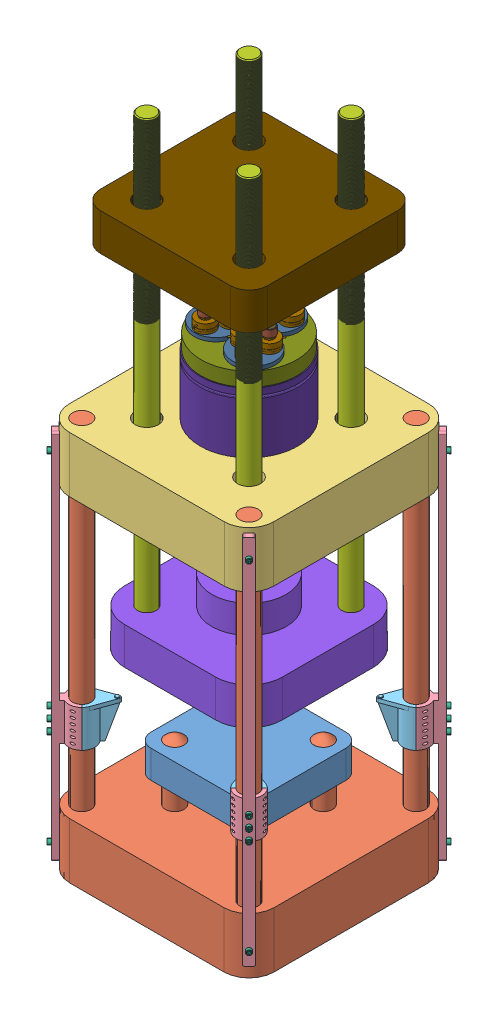
SolidWorks assembly calibration, configuration Default. Lengths in mm.
Overall size (2375.32 7055.28 2375.32).
136 component instances, 18 part files, 43 mates.
Components (placement in the parent):
- montaj alt tabla-1: montaj alt tabla [Default] at (833.2018 170.1758 2167.2273) size (2200.07 4200.02 2200.07)
  - 2 no-3: 2 no [Default] at (132.7753 591.3083 1009.2189) size (1200 300 1200)
  - 1no-3: 1no [Default] at (132.7613 -308.6894 1003.0525) x (1 -0.000003 -0.000025) z (0.000025 -0.000004 1) size (2200 4200 2200)
- orta tabla-1: orta tabla [Default] at (965.9753 3461.4864 3170.2945) x (1 -0.000003 -0.000025) z (0.000025 -0.000004 1) size (2200 900 2200)
- sap montaj-5: sap montaj [Default] at (1404.482 -143.561 155.1917) x (0.707124 -0.000005 0.707089) z (-0.707089 -0.000001 0.707124) size (568.89 4000 280)
  - sap-1: sap [Default] at (549.0564 1205.0583 2442.1143) size (230.77 4000 280)
  - no5-1: no5 [Default] at (549.0564 1605.0583 2442.1143) size (302.12 417 280)
  - socket head cap screw_am-6: socket head cap screw_am [B18.3.1M - 16 x 2.0 x 80 Hex SHCS -- 44NHX] at (503.0564 1555.0583 2562.1143) size (96 24 24)
  - socket head cap screw_am-7: socket head cap screw_am [B18.3.1M - 16 x 2.0 x 80 Hex SHCS -- 44NHX] at (503.0564 1495.0583 2562.1143) size (96 24 24)
  - socket head cap screw_am-8: socket head cap screw_am [B18.3.1M - 16 x 2.0 x 80 Hex SHCS -- 44NHX] at (503.0564 1375.0583 2562.1143) x (1 0 0) z (0 0.323103 0.946364) size (96 24 24)
  - socket head cap screw_am-9: socket head cap screw_am [B18.3.1M - 16 x 2.0 x 80 Hex SHCS -- 44NHX] at (503.0564 1255.0583 2562.1143) size (96 24 24)
  - socket head cap screw_am-10: socket head cap screw_am [B18.3.1M - 16 x 2.0 x 80 Hex SHCS -- 44NHX] at (503.0564 1315.0583 2322.1143) size (96 24 24)
  - socket head cap screw_am-11: socket head cap screw_am [B18.3.1M - 16 x 2.0 x 80 Hex SHCS -- 44NHX] at (503.0564 1435.0583 2562.1143) x (1 0 0) z (0 0 -1) size (96 24 24)
  - socket head cap screw_am-12: socket head cap screw_am [B18.3.1M - 16 x 2.0 x 80 Hex SHCS -- 44NHX] at (503.0564 1255.0583 2322.1143) size (96 24 24)
  - socket head cap screw_am-13: socket head cap screw_am [B18.3.1M - 16 x 2.0 x 80 Hex SHCS -- 44NHX] at (503.0564 1375.0583 2322.1143) size (96 24 24)
  - socket head cap screw_am-14: socket head cap screw_am [B18.3.1M - 16 x 2.0 x 80 Hex SHCS -- 44NHX] at (503.0564 1315.0583 2562.1143) x (1 0 0) z (0 -0.989637 0.143592) size (96 24 24)
  - socket head cap screw_am-15: socket head cap screw_am [B18.3.1M - 16 x 2.0 x 80 Hex SHCS -- 44NHX] at (503.0564 1555.0583 2322.1143) size (96 24 24)
  - socket head cap screw_am-16: socket head cap screw_am [B18.3.1M - 16 x 2.0 x 80 Hex SHCS -- 44NHX] at (503.0564 1495.0583 2322.1143) size (96 24 24)
  - socket head cap screw_am-17: socket head cap screw_am [B18.3.1M - 16 x 2.0 x 80 Hex SHCS -- 44NHX] at (503.0564 1435.0583 2322.1143) size (96 24 24)
  - socket head cap screw_am-19: socket head cap screw_am [B18.3.1M - 36 x 4.0 x 80 Hex SHCS -- 80NHX] at (282.2894 1285.0583 2442.1143) size (116 54 54)
  - socket head cap screw_am-18: socket head cap screw_am [B18.3.1M - 36 x 4.0 x 80 Hex SHCS -- 80NHX] at (282.2894 1525.0583 2442.1143) x (1 0 0) z (0 0.987098 -0.160117) size (116 54 54)
  - socket head cap screw_am-20: socket head cap screw_am [B18.3.1M - 36 x 4.0 x 80 Hex SHCS -- 80NHX] at (282.2894 1405.0583 2442.1143) x (1 0 0) z (0 0.982449 -0.18653) size (116 54 54)
- sap montaj-6: sap montaj [Default] at (527.4443 -93.5827 6185.3679) x (-0.707124 0.000005 -0.707089) z (0.707089 0.000001 -0.707124) size (568.89 4000 280)
  - sap-1: sap [Default] at (549.0564 1205.0583 2442.1143) size (230.77 4000 280)
  - no5-1: no5 [Default] at (549.0564 1605.0583 2442.1143) size (302.12 417 280)
  - socket head cap screw_am-6: socket head cap screw_am [B18.3.1M - 16 x 2.0 x 80 Hex SHCS -- 44NHX] at (503.0564 1555.0583 2562.1143) size (96 24 24)
  - socket head cap screw_am-7: socket head cap screw_am [B18.3.1M - 16 x 2.0 x 80 Hex SHCS -- 44NHX] at (503.0564 1495.0583 2562.1143) size (96 24 24)
  - socket head cap screw_am-8: socket head cap screw_am [B18.3.1M - 16 x 2.0 x 80 Hex SHCS -- 44NHX] at (503.0564 1375.0583 2562.1143) x (1 0 0) z (0 0.323103 0.946364) size (96 24 24)
  - socket head cap screw_am-9: socket head cap screw_am [B18.3.1M - 16 x 2.0 x 80 Hex SHCS -- 44NHX] at (503.0564 1255.0583 2562.1143) size (96 24 24)
  - socket head cap screw_am-10: socket head cap screw_am [B18.3.1M - 16 x 2.0 x 80 Hex SHCS -- 44NHX] at (503.0564 1315.0583 2322.1143) size (96 24 24)
  - socket head cap screw_am-11: socket head cap screw_am [B18.3.1M - 16 x 2.0 x 80 Hex SHCS -- 44NHX] at (503.0564 1435.0583 2562.1143) x (1 0 0) z (0 0 -1) size (96 24 24)
  - socket head cap screw_am-12: socket head cap screw_am [B18.3.1M - 16 x 2.0 x 80 Hex SHCS -- 44NHX] at (503.0564 1255.0583 2322.1143) size (96 24 24)
  - socket head cap screw_am-13: socket head cap screw_am [B18.3.1M - 16 x 2.0 x 80 Hex SHCS -- 44NHX] at (503.0564 1375.0583 2322.1143) size (96 24 24)
  - socket head cap screw_am-14: socket head cap screw_am [B18.3.1M - 16 x 2.0 x 80 Hex SHCS -- 44NHX] at (503.0564 1315.0583 2562.1143) x (1 0 0) z (0 -0.989637 0.143592) size (96 24 24)
  - socket head cap screw_am-15: socket head cap screw_am [B18.3.1M - 16 x 2.0 x 80 Hex SHCS -- 44NHX] at (503.0564 1555.0583 2322.1143) size (96 24 24)
  - socket head cap screw_am-16: socket head cap screw_am [B18.3.1M - 16 x 2.0 x 80 Hex SHCS -- 44NHX] at (503.0564 1495.0583 2322.1143) size (96 24 24)
  - socket head cap screw_am-17: socket head cap screw_am [B18.3.1M - 16 x 2.0 x 80 Hex SHCS -- 44NHX] at (503.0564 1435.0583 2322.1143) size (96 24 24)
  - socket head cap screw_am-19: socket head cap screw_am [B18.3.1M - 36 x 4.0 x 80 Hex SHCS -- 80NHX] at (282.2894 1285.0583 2442.1143) size (116 54 54)
  - socket head cap screw_am-18: socket head cap screw_am [B18.3.1M - 36 x 4.0 x 80 Hex SHCS -- 80NHX] at (282.2894 1525.0583 2442.1143) x (1 0 0) z (0 0.987098 -0.160117) size (116 54 54)
  - socket head cap screw_am-20: socket head cap screw_am [B18.3.1M - 36 x 4.0 x 80 Hex SHCS -- 80NHX] at (282.2894 1405.0583 2442.1143) x (1 0 0) z (0 0.982449 -0.18653) size (116 54 54)
- sap montaj-7: sap montaj [Default] at (-2049.1249 -143.5598 2731.7608) x (0.707089 0.000001 -0.707124) z (0.707124 -0.000005 0.707089) size (568.89 4000 280)
  - sap-1: sap [Default] at (549.0564 1205.0583 2442.1143) size (230.77 4000 280)
  - no5-1: no5 [Default] at (549.0564 1605.0583 2442.1143) size (302.12 417 280)
  - socket head cap screw_am-6: socket head cap screw_am [B18.3.1M - 16 x 2.0 x 80 Hex SHCS -- 44NHX] at (503.0564 1555.0583 2562.1143) size (96 24 24)
  - socket head cap screw_am-7: socket head cap screw_am [B18.3.1M - 16 x 2.0 x 80 Hex SHCS -- 44NHX] at (503.0564 1495.0583 2562.1143) size (96 24 24)
  - socket head cap screw_am-8: socket head cap screw_am [B18.3.1M - 16 x 2.0 x 80 Hex SHCS -- 44NHX] at (503.0564 1375.0583 2562.1143) x (1 0 0) z (0 0.323103 0.946364) size (96 24 24)
  - socket head cap screw_am-9: socket head cap screw_am [B18.3.1M - 16 x 2.0 x 80 Hex SHCS -- 44NHX] at (503.0564 1255.0583 2562.1143) size (96 24 24)
  - socket head cap screw_am-10: socket head cap screw_am [B18.3.1M - 16 x 2.0 x 80 Hex SHCS -- 44NHX] at (503.0564 1315.0583 2322.1143) size (96 24 24)
  - socket head cap screw_am-11: socket head cap screw_am [B18.3.1M - 16 x 2.0 x 80 Hex SHCS -- 44NHX] at (503.0564 1435.0583 2562.1143) x (1 0 0) z (0 0 -1) size (96 24 24)
  - socket head cap screw_am-12: socket head cap screw_am [B18.3.1M - 16 x 2.0 x 80 Hex SHCS -- 44NHX] at (503.0564 1255.0583 2322.1143) size (96 24 24)
  - socket head cap screw_am-13: socket head cap screw_am [B18.3.1M - 16 x 2.0 x 80 Hex SHCS -- 44NHX] at (503.0564 1375.0583 2322.1143) size (96 24 24)
  - socket head cap screw_am-14: socket head cap screw_am [B18.3.1M - 16 x 2.0 x 80 Hex SHCS -- 44NHX] at (503.0564 1315.0583 2562.1143) x (1 0 0) z (0 -0.989637 0.143592) size (96 24 24)
  - socket head cap screw_am-15: socket head cap screw_am [B18.3.1M - 16 x 2.0 x 80 Hex SHCS -- 44NHX] at (503.0564 1555.0583 2322.1143) size (96 24 24)
  - socket head cap screw_am-16: socket head cap screw_am [B18.3.1M - 16 x 2.0 x 80 Hex SHCS -- 44NHX] at (503.0564 1495.0583 2322.1143) size (96 24 24)
  - socket head cap screw_am-17: socket head cap screw_am [B18.3.1M - 16 x 2.0 x 80 Hex SHCS -- 44NHX] at (503.0564 1435.0583 2322.1143) size (96 24 24)
  - socket head cap screw_am-19: socket head cap screw_am [B18.3.1M - 36 x 4.0 x 80 Hex SHCS -- 80NHX] at (282.2894 1285.0583 2442.1143) size (116 54 54)
  - socket head cap screw_am-18: socket head cap screw_am [B18.3.1M - 36 x 4.0 x 80 Hex SHCS -- 80NHX] at (282.2894 1525.0583 2442.1143) x (1 0 0) z (0 0.987098 -0.160117) size (116 54 54)
  - socket head cap screw_am-20: socket head cap screw_am [B18.3.1M - 36 x 4.0 x 80 Hex SHCS -- 80NHX] at (282.2894 1405.0583 2442.1143) x (1 0 0) z (0 0.982449 -0.18653) size (116 54 54)
- sap montaj-8: sap montaj [Default] at (3981.0511 -143.5839 3608.7986) x (-0.707089 -0.000001 0.707124) z (-0.707124 0.000005 -0.707089) size (568.89 4000 280)
  - sap-1: sap [Default] at (549.0564 1205.0583 2442.1143) size (230.77 4000 280)
  - no5-1: no5 [Default] at (549.0564 1605.0583 2442.1143) size (302.12 417 280)
  - socket head cap screw_am-6: socket head cap screw_am [B18.3.1M - 16 x 2.0 x 80 Hex SHCS -- 44NHX] at (503.0564 1555.0583 2562.1143) size (96 24 24)
  - socket head cap screw_am-7: socket head cap screw_am [B18.3.1M - 16 x 2.0 x 80 Hex SHCS -- 44NHX] at (503.0564 1495.0583 2562.1143) size (96 24 24)
  - socket head cap screw_am-8: socket head cap screw_am [B18.3.1M - 16 x 2.0 x 80 Hex SHCS -- 44NHX] at (503.0564 1375.0583 2562.1143) x (1 0 0) z (0 0.323103 0.946364) size (96 24 24)
  - socket head cap screw_am-9: socket head cap screw_am [B18.3.1M - 16 x 2.0 x 80 Hex SHCS -- 44NHX] at (503.0564 1255.0583 2562.1143) size (96 24 24)
  - socket head cap screw_am-10: socket head cap screw_am [B18.3.1M - 16 x 2.0 x 80 Hex SHCS -- 44NHX] at (503.0564 1315.0583 2322.1143) size (96 24 24)
  - socket head cap screw_am-11: socket head cap screw_am [B18.3.1M - 16 x 2.0 x 80 Hex SHCS -- 44NHX] at (503.0564 1435.0583 2562.1143) x (1 0 0) z (0 0 -1) size (96 24 24)
  - socket head cap screw_am-12: socket head cap screw_am [B18.3.1M - 16 x 2.0 x 80 Hex SHCS -- 44NHX] at (503.0564 1255.0583 2322.1143) size (96 24 24)
  - socket head cap screw_am-13: socket head cap screw_am [B18.3.1M - 16 x 2.0 x 80 Hex SHCS -- 44NHX] at (503.0564 1375.0583 2322.1143) size (96 24 24)
  - socket head cap screw_am-14: socket head cap screw_am [B18.3.1M - 16 x 2.0 x 80 Hex SHCS -- 44NHX] at (503.0564 1315.0583 2562.1143) x (1 0 0) z (0 -0.989637 0.143592) size (96 24 24)
  - socket head cap screw_am-15: socket head cap screw_am [B18.3.1M - 16 x 2.0 x 80 Hex SHCS -- 44NHX] at (503.0564 1555.0583 2322.1143) size (96 24 24)
  - socket head cap screw_am-16: socket head cap screw_am [B18.3.1M - 16 x 2.0 x 80 Hex SHCS -- 44NHX] at (503.0564 1495.0583 2322.1143) size (96 24 24)
  - socket head cap screw_am-17: socket head cap screw_am [B18.3.1M - 16 x 2.0 x 80 Hex SHCS -- 44NHX] at (503.0564 1435.0583 2322.1143) size (96 24 24)
  - socket head cap screw_am-19: socket head cap screw_am [B18.3.1M - 36 x 4.0 x 80 Hex SHCS -- 80NHX] at (282.2894 1285.0583 2442.1143) size (116 54 54)
  - socket head cap screw_am-18: socket head cap screw_am [B18.3.1M - 36 x 4.0 x 80 Hex SHCS -- 80NHX] at (282.2894 1525.0583 2442.1143) x (1 0 0) z (0 0.987098 -0.160117) size (116 54 54)
  - socket head cap screw_am-20: socket head cap screw_am [B18.3.1M - 36 x 4.0 x 80 Hex SHCS -- 80NHX] at (282.2894 1405.0583 2442.1143) x (1 0 0) z (0 0.982449 -0.18653) size (116 54 54)
- socket head cap screw_am-1: socket head cap screw_am [B18.3.1M - 36 x 4.0 x 90 Hex SHCS -- 90NHX] at (2054.6363 3811.4783 4258.9015) x (-0.707124 0.000005 -0.707089) z (-0.5112 -0.690889 0.511221) size (126 54 54)
- socket head cap screw_am-2: socket head cap screw_am [B18.3.1M - 36 x 4.0 x 90 Hex SHCS -- 90NHX] at (2054.5819 3761.4872 2081.6359) x (-0.707089 -0.000001 0.707124) z (-0.707124 0.000008 -0.707089) size (126 54 54)
- socket head cap screw_am-3: socket head cap screw_am [B18.3.1M - 36 x 4.0 x 90 Hex SHCS -- 90NHX] at (-122.6293 3761.4856 4258.9556) x (0.707089 0.000001 -0.707124) z (0.500005 -0.707118 0.499979) size (126 54 54)
- socket head cap screw_am-4: socket head cap screw_am [B18.3.1M - 36 x 4.0 x 90 Hex SHCS -- 90NHX] at (-122.6836 3761.4946 2081.6902) x (0.707124 -0.000005 0.707089) z (-0.707089 0.000002 0.707124) size (126 54 54)
- socket head cap screw_am-6: socket head cap screw_am [B18.3.1M - 36 x 4.0 x 120 Hex SHCS -- 84NHX] at (-122.6417 111.4856 4258.9407) x (0.707089 0.000001 -0.707124) z (0.707124 -0.000001 0.707089) size (156 54 54)
- socket head cap screw_am-8: socket head cap screw_am [B18.3.1M - 36 x 4.0 x 120 Hex SHCS -- 84NHX] at (-122.696 111.4946 2081.6752) x (0.707124 -0.000005 0.707089) z (0.124169 -0.98446 -0.124182) size (156 54 54)
- socket head cap screw_am-11: socket head cap screw_am [B18.3.1M - 36 x 4.0 x 120 Hex SHCS -- 84NHX] at (2054.5695 111.4872 2081.6209) x (-0.707089 -0.000001 0.707124) z (-0.707124 0.000001 -0.707089) size (156 54 54)
- socket head cap screw_am-14: socket head cap screw_am [B18.3.1M - 36 x 4.0 x 120 Hex SHCS -- 84NHX] at (2054.624 161.4783 4258.8866) x (-0.707124 0.000005 -0.707089) z (0.707089 -0.000004 -0.707124) size (156 54 54)
- dişli boru-1: dişli boru [Default] at (1515.957 2116.7548 2620.2753) x (-0.603975 -0.000001 0.797003) z (-0.797003 0.000005 -0.603975) size (200 4800 200)
- dişli boru-2: dişli boru [Default] at (1515.9844 2116.7503 3720.2753) x (-0.622585 -0.000001 0.782552) z (-0.782552 0.000005 -0.622585) size (200 4800 200)
- dişli boru-3: dişli boru [Default] at (415.957 2116.7586 2620.3027) x (-0.568311 -0.000001 0.822814) z (-0.822814 0.000005 -0.568311) size (200 4800 200)
- dişli boru-4: dişli boru [Default] at (415.9844 2116.7541 3720.3027) x (0.992602 -0.000004 0.12141) z (-0.12141 -0.000004 0.992602) size (200 4800 200)
- minik tabla-1: minik tabla [Default] at (965.97 1916.7544 3170.2882) x (1 -0.000003 -0.000025) z (0.000025 -0.000004 1) size (1700 735 1700)
- loadcell montaj-1: loadcell montaj [Default] at (1570.4653 4300.1001 2998.6885) x (-0.993338 0.000003 0.11524) z (-0.11524 0.000004 -0.993338) size (1050 1634.29 1115.82)
  - loadcelly-1: loadcelly [Default] at (983.2366 597.3849 -108.9473) x (0.988948 0 0.148261) z (-0.148261 0 0.988948) size (200 128 227.95)
  - en altın üstü taban-2: en altın üstü taban [Default] at (554.4979 601.3849 163.9457) x (0.759209 0 -0.650847) z (0.650847 0 0.759209) size (462.49 80 462.49)
  - en altın üstü taban-3: en altın üstü taban [Default] at (423.8247 601.3849 -290.1112) x (-0.937238 0 0.34869) z (-0.34869 0 -0.937238) size (462.49 80 462.49)
  - en altın üstü taban-4: en altın üstü taban [Default] at (882.3861 601.3849 -176.249) x (-0.999567 0 -0.029427) z (0.029427 0 -0.999567) size (462.49 80 462.49)
  - loadcelly-2: loadcelly [Default] at (773.6759 597.3849 -122.5608) x (0.537249 0 0.843424) z (-0.843424 0 0.537249) size (200 128 227.95)
  - loadcelly-3: loadcelly [Default] at (890.2459 597.3849 -297.239) x (0.967506 0 0.252847) z (-0.252847 0 0.967506) size (200 128 227.95)
  - loadcelly-4: loadcelly [Default] at (542.5834 597.3849 -265.6832) x (0.668199 0 0.743982) z (-0.743982 0 0.668199) size (200 128 227.95)
  - loadcelly-5: loadcelly [Default] at (385.6007 597.3849 -405.1733) x (0.741954 0 -0.67045) z (0.67045 0 0.741954) size (200 128 227.95)
  - loadcelly-6: loadcelly [Default] at (343.2901 597.3849 -199.4772) x (-0.630513 0 -0.776179) z (0.776179 0 -0.630513) size (200 128 227.95)
  - loadcelly-7: loadcelly [Default] at (630.0986 597.3849 258.7343) x (-0.987264 0 0.159091) z (-0.159091 0 -0.987264) size (200 128 227.95)
  - loadcelly-8: loadcelly [Default] at (598.7868 597.3849 51.0792) x (0.625619 0 0.780128) z (-0.780128 0 0.625619) size (200 128 227.95)
  - loadcelly-9: loadcelly [Default] at (434.6082 597.3849 182.0236) x (-0.980419 0 -0.196921) z (0.196921 0 -0.980419) size (200 128 227.95)
  - load cell üst kısım2-3: load cell üst kısım2 [Default] at (630.0986 725.6766 258.7343) x (0.894719 0 0.44663) z (-0.44663 0 0.894719) size (120 75 120)
  - load cell üst kısım2-5: load cell üst kısım2 [Default] at (890.2459 725.6766 -297.239) x (-0.037968 0 0.999279) z (-0.999279 0 -0.037968) size (120 75 120)
  - load cell üst kısım2-8: load cell üst kısım2 [Default] at (343.2901 725.6766 -199.4772) x (0.378524 0 -0.925591) z (0.925591 0 0.378524) size (120 75 120)
  - load cell üst kısım2-9: load cell üst kısım2 [Default] at (542.5834 725.6766 -265.6832) x (-0.69591 0 0.718129) z (-0.718129 0 -0.69591) size (120 75 120)
  - load cell üst kısım2-10: load cell üst kısım2 [Default] at (983.2366 725.6766 -108.9473) x (-0.037968 0 0.999279) z (-0.999279 0 -0.037968) size (120 75 120)
  - load cell üst kısım2-12: load cell üst kısım2 [Default] at (773.6759 725.6766 -122.5608) x (-0.037968 0 0.999279) z (-0.999279 0 -0.037968) size (120 75 120)
  - load cell üst kısım2-13: load cell üst kısım2 [Default] at (598.7868 725.6766 51.0792) x (-0.921584 0 0.38818) z (-0.38818 0 -0.921584) size (120 75 120)
  - load cell üst kısım2-14: load cell üst kısım2 [Default] at (434.6082 725.6766 182.0236) x (-0.316593 0 0.948562) z (-0.948562 0 -0.316593) size (120 75 120)
  - load cell üst kısım2-15: load cell üst kısım2 [Default] at (385.6007 725.6766 -405.1733) x (-0.389198 0 0.921154) z (-0.921154 0 -0.389198) size (120 75 120)
  - ara parça-2: ara parça [Default] at (890.2459 800.6766 -297.239) x (0.998984 0 0.045074) z (-0.045074 0 0.998984) size (100 140 100)
  - ara parça-3: ara parça [Default] at (773.6759 800.6766 -122.5608) x (0.998984 0 0.045074) z (-0.045074 0 0.998984) size (100 140 100)
  - ara parça-4: ara parça [Default] at (598.7868 800.6766 51.0792) x (0.998984 0 0.045074) z (-0.045074 0 0.998984) size (100 140 100)
  - ara parça-5: ara parça [Default] at (343.2901 800.6766 -199.4772) x (-0.246067 0 0.969253) z (-0.969253 0 -0.246067) size (100 140 100)
  - ara parça-6: ara parça [Default] at (385.6007 800.6766 -405.1733) x (0.998984 0 0.045074) z (-0.045074 0 0.998984) size (100 140 100)
  - ara parça-7: ara parça [Default] at (983.2366 800.6766 -108.9473) x (-0.038937 0 0.999242) z (-0.999242 0 -0.038937) size (100 140 100)
  - ara parça-8: ara parça [Default] at (542.5834 800.6766 -265.6832) x (0.998984 0 0.045074) z (-0.045074 0 0.998984) size (100 140 100)
  - ara parça-9: ara parça [Default] at (434.6082 800.6766 182.0236) x (0.998984 0 0.045074) z (-0.045074 0 0.998984) size (100 140 100)
  - ara parça-10: ara parça [Default] at (630.0986 800.6766 258.7343) x (0.998984 0 0.045074) z (-0.045074 0 0.998984) size (100 140 100)
  - load cell üst kısım3-1: load cell üst kısım3 [Default] at (630.0986 940.6766 258.7343) x (0.606184 0 0.795325) z (-0.795325 0 0.606184) size (120 75 120)
  - load cell üst kısım3-2: load cell üst kısım3 [Default] at (434.6082 1015.6766 182.0236) x (0.951217 0 0.308522) z (0.308522 0 -0.951217) size (120 75 120)
  - load cell üst kısım3-3: load cell üst kısım3 [Default] at (598.7868 940.6766 51.0792) size (120 75 120)
  - load cell üst kısım3-4: load cell üst kısım3 [Default] at (343.2901 940.6766 -199.4772) size (120 75 120)
  - load cell üst kısım3-5: load cell üst kısım3 [Default] at (890.2459 940.6766 -297.239) size (120 75 120)
  - load cell üst kısım3-6: load cell üst kısım3 [Default] at (542.5834 940.6766 -265.6832) size (120 75 120)
  - load cell üst kısım3-7: load cell üst kısım3 [Default] at (385.6007 940.6766 -405.1733) size (120 75 120)
  - load cell üst kısım3-8: load cell üst kısım3 [Default] at (983.2366 940.6766 -108.9473) size (120 75 120)
  - load cell üst kısım3-9: load cell üst kısım3 [Default] at (773.6759 940.6766 -122.5608) size (120 75 120)
  - yeni en üstün altı-1: yeni en üstün altı [Default] at (554.4979 1015.6766 163.9457) size (462.49 80 462.49)
  - yeni en üstün altı-2: yeni en üstün altı [Default] at (882.3861 1015.6766 -176.249) size (462.49 80 462.49)
  - yeni en üstün altı-3: yeni en üstün altı [Default] at (423.8247 1015.6766 -290.1112) size (462.49 80 462.49)
  - en üst yeni-1: en üst yeni [Default] at (620.2363 1095.6766 -100.8049) size (1028.07 150 1028.07)
  - taban kısmı.2.-1: taban kısmı.2. [Default] at (620.2363 561.3849 -100.8049) size (1028.07 150 1028.07)
  - siyah kısım-1: siyah kısım [Default] at (620.2363 -388.6151 -100.8049) size (1050 800 1050)
- part4-1: part4 [Default] at (965.9965 5695.7781 3170.29) x (1 -0.000003 0) z (0 -0.000004 1) size (1800 550 1800)
Mates (geometry in assembly coordinates):
- Çakışık2: coincident aligned: circle of montaj alt tabla-1/1no-3; circle of orta tabla-1
- Çakışık12: coincident anti-aligned: cylinder of montaj alt tabla-1/1no-3 through (65.9548 4061.4931 2270.3194) axis (-0.000003 -1 -0.000004) radius 100; circle of orta tabla-1
- Eş Merkezli35: concentric aligned: cylinder of montaj alt tabla-1/1no-3 through (65.9548 4061.4931 2270.3194) axis (-0.000003 -1 -0.000004) radius 100; cylinder of sap montaj-5/sap-1 through (65.946 1461.4931 2270.3088) axis (-0.000003 -1 -0.000004) radius 100
- Eş Merkezli36: concentric aligned: cylinder of montaj alt tabla-1/1no-3 through (-12.5529 111.4937 2191.8128) axis (-0.707124 0.000005 -0.707089) radius 18; cylinder of sap montaj-5/sap-1 through (-54.812 111.494 2149.5558) axis (-0.707124 0.000005 -0.707089) radius 18
- Eş Merkezli37: concentric aligned: cylinder of montaj alt tabla-1/1no-3 through (1865.9997 4061.4797 4070.2745) axis (-0.000003 -1 -0.000004) radius 100; cylinder of sap montaj-6/sap-1 through (1865.9911 1511.4797 4070.2641) axis (-0.000003 -1 -0.000004) radius 100
- Eş Merkezli38: concentric aligned: cylinder of montaj alt tabla-1/1no-3 through (1944.4809 161.4791 4148.749) axis (0.707124 -0.000005 0.707089) radius 18; cylinder of sap montaj-6/sap-1 through (1986.74 161.4788 4191.006) axis (0.707124 -0.000005 0.707089) radius 18
- Eş Merkezli39: concentric anti-aligned: cylinder of montaj alt tabla-1/1no-3 through (65.9997 4061.4858 4070.3194) axis (-0.000003 -1 -0.000004) radius 100; cylinder of sap montaj-7/no5-1 through (65.9896 1061.4858 4070.3071) axis (0.000003 1 0.000004) radius 140
- Eş Merkezli40: concentric aligned: cylinder of montaj alt tabla-1/1no-3 through (-12.5041 111.4857 4148.7976) axis (-0.707089 -0.000001 0.707124) radius 18; cylinder of sap montaj-7/sap-1 through (-54.7611 111.4857 4191.0567) axis (-0.707089 -0.000001 0.707124) radius 18
- Çakışık28: coincident anti-aligned: cylinder of montaj alt tabla-1/1no-3 through (1865.9548 4061.487 2270.2745) axis (-0.000003 -1 -0.000004) radius 100; circle of sap montaj-8/sap-1
- Eş Merkezli41: concentric aligned: cylinder of montaj alt tabla-1/1no-3 through (1944.4319 111.4871 2191.7639) axis (0.707089 0.000001 -0.707124) radius 18; cylinder of sap montaj-8/sap-1 through (1986.6889 111.4871 2149.5048) axis (0.707089 0.000001 -0.707124) radius 18
- Eş Merkezli43: concentric aligned: cylinder of sap montaj-5/sap-1 through (-6.7152 3761.4937 2197.6528) axis (-0.707124 0.000005 -0.707089) radius 18; cylinder of socket head cap screw_am-4 through (-145.1348 3761.4947 2059.2401) axis (-0.707124 0.000005 -0.707089) radius 18
- Çakışık30: coincident anti-aligned: plane of sap montaj-5/sap-1 through (-76.0273 -18.5056 2085.9161) normal (-0.707124 0.000005 -0.707089); plane of socket head cap screw_am-4 through (-97.227 3788.4944 2107.1454) normal (0.707124 -0.000005 0.707089)
- Eş Merkezli44: concentric aligned: cylinder of sap montaj-7/sap-1 through (-6.6667 3761.4857 4142.9872) axis (-0.707089 -0.000001 0.707124) radius 18; cylinder of socket head cap screw_am-3 through (-145.0794 3761.4856 4281.4068) axis (-0.707089 -0.000001 0.707124) radius 18
- Çakışık31: coincident anti-aligned: plane of sap montaj-7/sap-1 through (-118.4006 -18.5142 4212.271) normal (-0.707089 -0.000001 0.707124); plane of socket head cap screw_am-3 through (-83.6735 3780.5772 4246.999) normal (0.707089 0.000001 -0.707124)
- Çakışık32: coincident anti-aligned: plane of sap montaj-6/sap-1 through (2007.9544 31.4784 4254.6445) normal (0.707124 -0.000005 0.707089); plane of socket head cap screw_am-1 through (2042.3698 3791.9585 4220.2555) normal (-0.707124 0.000005 -0.707089)
- Eş Merkezli50: concentric aligned: cylinder of sap montaj-6/sap-1 through (1938.6679 3811.4791 4142.9389) axis (0.707124 -0.000005 0.707089) radius 18; cylinder of socket head cap screw_am-1 through (2077.0875 3811.4781 4281.3516) axis (0.707124 -0.000005 0.707089) radius 18
- Çakışık33: coincident anti-aligned: plane of sap montaj-8/sap-1 through (2050.3276 -18.513 2128.2895) normal (0.707089 0.000001 -0.707124); plane of socket head cap screw_am-2 through (2029.1268 3788.4872 2107.0925) normal (-0.707089 -0.000001 0.707124)
- Eş Merkezli51: concentric aligned: cylinder of sap montaj-8/sap-1 through (1938.6192 3761.4871 2197.6043) axis (0.707089 0.000001 -0.707124) radius 18; cylinder of socket head cap screw_am-2 through (2077.0319 3761.4872 2059.1847) axis (0.707089 0.000001 -0.707124) radius 18
- Çakışık34: coincident anti-aligned: plane of sap montaj-7/sap-1 through (-118.4006 -18.5142 4212.271) normal (-0.707089 -0.000001 0.707124); plane of socket head cap screw_am-6 through (-97.1864 138.4856 4233.4842) normal (0.707089 0.000001 -0.707124)
- Eş Merkezli52: concentric aligned: cylinder of sap montaj-7/sap-1 through (-54.7611 111.4857 4191.0567) axis (-0.707089 -0.000001 0.707124) radius 18; cylinder of socket head cap screw_am-6 through (-145.0917 111.4856 4281.3919) axis (-0.707089 -0.000001 0.707124) radius 18
- Çakışık38: coincident aligned: circle of sap montaj-5/sap-1; cylinder of socket head cap screw_am-8 through (-145.1472 111.4947 2059.2251) axis (-0.707124 0.000005 -0.707089) radius 18
- Eş Merkezli58: concentric aligned: circle of sap montaj-5/sap-1; circle of socket head cap screw_am-8
- Çakışık39: coincident aligned: plane of sap montaj-5/sap-1 through (-76.0273 -18.5056 2085.9161) normal (-0.707124 0.000005 -0.707089); circle of socket head cap screw_am-8
- Eş Merkezli59: concentric aligned: cylinder of sap montaj-8/sap-1 through (1986.6889 111.4871 2149.5048) axis (0.707089 0.000001 -0.707124) radius 18; cylinder of socket head cap screw_am-11 through (2077.0196 111.4872 2059.1697) axis (0.707089 0.000001 -0.707124) radius 27
- Çakışık40: coincident anti-aligned: plane of sap montaj-8/sap-1 through (2050.3276 -18.513 2128.2895) normal (0.707089 0.000001 -0.707124); plane of socket head cap screw_am-11 through (2029.1143 138.4872 2107.0774) normal (-0.707089 -0.000001 0.707124)
- Çakışık41: coincident anti-aligned: plane of sap montaj-6/sap-1 through (2007.9544 31.4784 4254.6445) normal (0.707124 -0.000005 0.707089); plane of socket head cap screw_am-14 through (2029.1677 188.4784 4233.4314) normal (-0.707124 0.000005 -0.707089)
- Eş Merkezli66: concentric aligned: cylinder of sap montaj-6/sap-1 through (1986.74 161.4788 4191.006) axis (0.707124 -0.000005 0.707089) radius 18; cylinder of socket head cap screw_am-14 through (2077.0752 161.4781 4281.3366) axis (0.707124 -0.000005 0.707089) radius 18
- Eş Merkezli68: concentric aligned: cylinder of orta tabla-1 through (1515.9636 4061.4868 2620.2833) axis (-0.000003 -1 -0.000004) radius 125; cylinder of dişli boru-1 through (1515.9732 6916.7548 2620.295) axis (-0.000003 -1 -0.000004) radius 100
- Eş Merkezli69: concentric aligned: cylinder of orta tabla-1 through (1515.991 4061.4823 3720.2833) axis (-0.000003 -1 -0.000004) radius 125; cylinder of dişli boru-2 through (1516.0007 6916.7503 3720.295) axis (-0.000003 -1 -0.000004) radius 100
- Eş Merkezli70: concentric aligned: cylinder of orta tabla-1 through (415.991 4061.486 3720.3107) axis (-0.000003 -1 -0.000004) radius 125; cylinder of dişli boru-4 through (416.0007 6916.7541 3720.3224) axis (-0.000003 -1 -0.000004) radius 100
- Eş Merkezli71: concentric aligned: cylinder of orta tabla-1 through (415.9636 4061.4905 2620.3107) axis (-0.000003 -1 -0.000004) radius 125; cylinder of dişli boru-3 through (415.9732 6916.7586 2620.3224) axis (-0.000003 -1 -0.000004) radius 100
- Çakışık42: coincident anti-aligned: plane of dişli boru-2 through (1515.9844 2116.7503 3720.2753) normal (-0.000003 -1 -0.000004); plane of minik tabla-1 through (1515.9844 2116.7503 3720.2753) normal (0.000003 1 0.000004)
- Eş Merkezli72: concentric anti-aligned: cylinder of dişli boru-2 through (1516.0007 6916.7503 3720.295) axis (-0.000003 -1 -0.000004) radius 100; cylinder of minik tabla-1 through (1515.9844 2116.7503 3720.2753) axis (0.000003 1 0.000004) radius 100
- Eş Merkezli73: concentric anti-aligned: cylinder of dişli boru-1 through (1515.9732 6916.7548 2620.295) axis (-0.000003 -1 -0.000004) radius 100; cylinder of minik tabla-1 through (1515.957 2116.7548 2620.2753) axis (0.000003 1 0.000004) radius 100
- Eş Merkezli74: concentric anti-aligned: cylinder of dişli boru-3 through (415.9732 6916.7586 2620.3224) axis (-0.000003 -1 -0.000004) radius 100; cylinder of minik tabla-1 through (415.957 2116.7586 2620.3027) axis (0.000003 1 0.000004) radius 100
- Eş Merkezli75: concentric anti-aligned: cylinder of dişli boru-4 through (416.0007 6916.7541 3720.3224) axis (-0.000003 -1 -0.000004) radius 100; cylinder of minik tabla-1 through (415.9844 2116.7541 3720.3027) axis (0.000003 1 0.000004) radius 100
- Çakışık43: coincident anti-aligned: plane of dişli boru-1 through (1515.957 2116.7548 2620.2753) normal (-0.000003 -1 -0.000004); plane of minik tabla-1 through (1515.957 2116.7548 2620.2753) normal (0.000003 1 0.000004)
- Çakışık44: coincident aligned: circle of dişli boru-3; plane of minik tabla-1 through (415.957 2116.7586 2620.3027) normal (0.000003 1 0.000004)
- Çakışık45: coincident anti-aligned: plane of dişli boru-4 through (415.9844 2116.7541 3720.3027) normal (-0.000003 -1 -0.000004); plane of minik tabla-1 through (415.9844 2116.7541 3720.3027) normal (0.000003 1 0.000004)
- Eş Merkezli76: concentric anti-aligned: cylinder of orta tabla-1 through (965.9768 3911.4864 3170.2964) axis (0.000003 1 0.000004) radius 525; cylinder of loadcell montaj-1/siyah kısım-1 through (965.9795 4711.4864 3170.2996) axis (-0.000003 -1 -0.000004) radius 525
- Çakışık46: coincident anti-aligned: plane of orta tabla-1 through (965.9768 3911.4864 3170.2964) normal (0.000003 1 0.000004); plane of loadcell montaj-1/siyah kısım-1 through (965.9768 3911.4864 3170.2964) normal (-0.000003 -1 -0.000004)
- Eş Merkezli77: concentric anti-aligned: circle of dişli boru-2; circle of part4-1
- Çakışık47: coincident anti-aligned: plane of loadcell montaj-1/en üst yeni-1 through (965.9823 5545.7781 3170.3031) normal (0.000003 1 0.000004); plane of part4-1 through (965.996 5545.7781 3170.2893) normal (-0.000003 -1 -0.000004)
